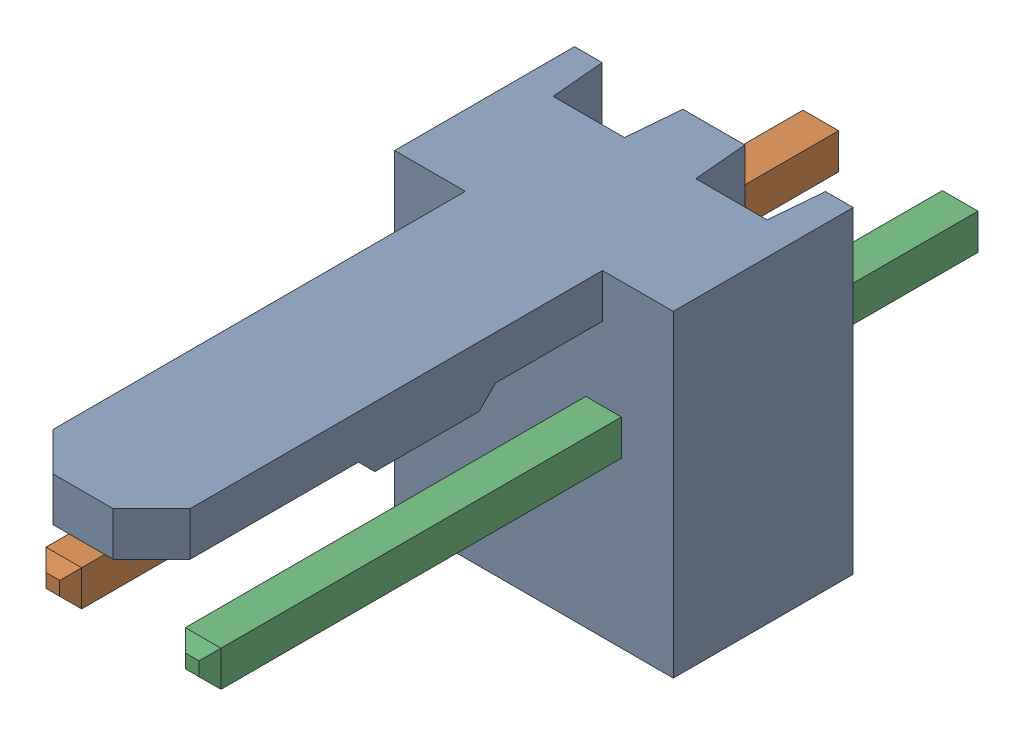
SolidWorks assembly Molex PCB 2 pin v2 (2), configuration Default. Lengths in mm.
Overall size (5.08 5.79 14.92).
3 component instances, 2 part files, 0 mates.
Components (placement in the parent):
- BASE9710016-1: BASE9710016 [Default] at (2.54 2.895 -8.22) size (5.08 5.79 11.5)
- PINO9710016-1: PINO9710016 [Default] at (1.27 3.325 -0.72) size (0.65 0.65 14.2)
- PINO9710016-2: PINO9710016 [Default] at (3.81 3.325 -0.72) size (0.65 0.65 14.2)
